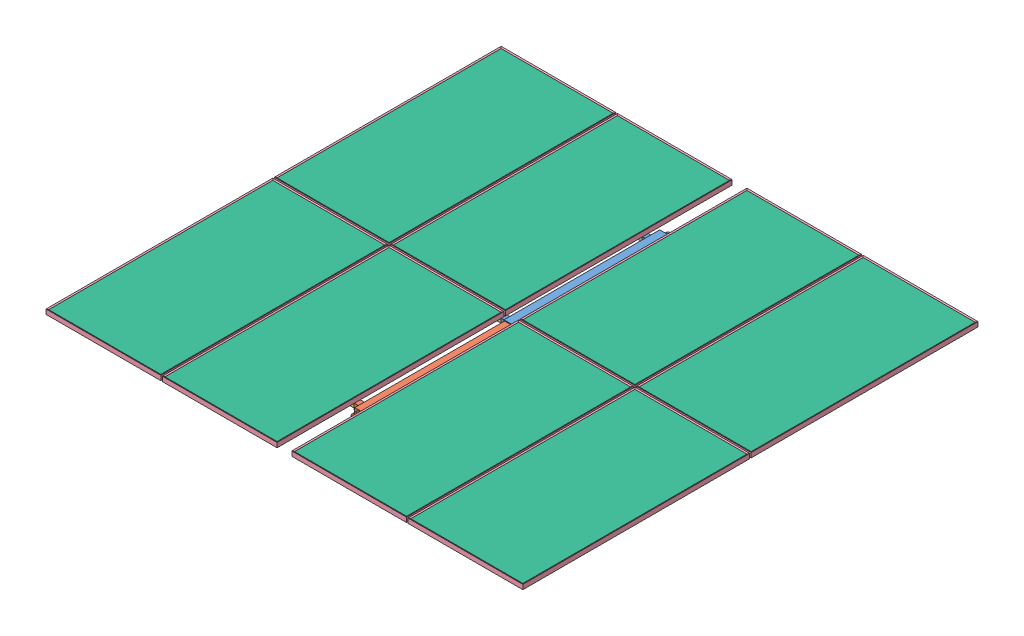
SolidWorks assembly SOLAR_ARRAY, configuration Default. Lengths in mm.
Overall size (4121.3 151.51 3933.6).
48 component instances, 7 part files, 65 mates.
Components (placement in the parent):
- SOLAR_FRAME_TELESCOPIC SLEEVE-1: SOLAR_FRAME_TELESCOPIC SLEEVE [Default] at (678.4072 800.4762 1616.3582) size (203.2 101.6 1384.3)
- SOLAR_FRAME_TELESCOPIC INSERT-1: SOLAR_FRAME_TELESCOPIC INSERT [Default] at (678.4072 800.4762 2911.7582) size (203.2 88.9 1612.9)
- SOLAR_FRAME_ARMBAR-1: SOLAR_FRAME_ARMBAR [Default] at (729.2072 800.4762 346.3582) x (0 0 1) z (-1 0 0) size (38.1 38.1 1828.8)
- SOLAR_FRAME_ARMBAR-2: SOLAR_FRAME_ARMBAR [Default] at (729.2072 800.4762 1565.5582) x (0 0 1) z (-1 0 0) size (38.1 38.1 1828.8)
- SOLAR_FRAME_ARMBAR-3: SOLAR_FRAME_ARMBAR [Default] at (729.2072 800.4762 2835.5582) x (0 0 -1) z (-1 0 0) size (38.1 38.1 1828.8)
- SOLAR_FRAME_ARMBAR-4: SOLAR_FRAME_ARMBAR [Default] at (627.6072 800.4762 346.3582) x (0 0 -1) z (1 0 0) size (38.1 38.1 1828.8)
- SOLAR_FRAME_ARMBAR-5: SOLAR_FRAME_ARMBAR [Default] at (627.6072 800.4762 1565.5582) x (0 0 -1) z (1 0 0) size (38.1 38.1 1828.8)
- SOLAR_FRAME_ARMBAR-6: SOLAR_FRAME_ARMBAR [Default] at (627.6072 800.4762 2835.5582) x (0 0 1) z (1 0 0) size (38.1 38.1 1828.8)
- SOLARPANEL-2: SOLARPANEL [Default] at (118.9072 880.5262 610.9582) size (992.9 40.66 1960.9)
  - SOLAR_PANEL_FRAM-1: SOLAR_PANEL_FRAM [Default] at origin size (992.9 40.66 1960.9)
  - SOLAR_PANEL_CELL-1: SOLAR_PANEL_CELL [Default] at (395 11.5 868.9962) x (0 0 -1) z (1 0 0) size (1956 21.55 988)
  - SOLAR_GLASS-1: SOLAR_GLASS [Default] at (0 11.8 0) x (0 0 1) z (-1 0 0) size (1956 3.2 988)
- SOLARPANEL-3: SOLARPANEL [Default] at (118.9072 880.5262 2583.6582) size (992.9 40.66 1960.9)
  - SOLAR_PANEL_FRAM-1: SOLAR_PANEL_FRAM [Default] at origin size (992.9 40.66 1960.9)
  - SOLAR_PANEL_CELL-1: SOLAR_PANEL_CELL [Default] at (395 11.5 868.9962) x (0 0 -1) z (1 0 0) size (1956 21.55 988)
  - SOLAR_GLASS-1: SOLAR_GLASS [Default] at (0 11.8 0) x (0 0 1) z (-1 0 0) size (1956 3.2 988)
- SOLARPANEL-4: SOLARPANEL [Default] at (1237.9072 880.5262 610.9582) size (992.9 40.66 1960.9)
  - SOLAR_PANEL_FRAM-1: SOLAR_PANEL_FRAM [Default] at origin size (992.9 40.66 1960.9)
  - SOLAR_PANEL_CELL-1: SOLAR_PANEL_CELL [Default] at (395 11.5 868.9962) x (0 0 -1) z (1 0 0) size (1956 21.55 988)
  - SOLAR_GLASS-1: SOLAR_GLASS [Default] at (0 11.8 0) x (0 0 1) z (-1 0 0) size (1956 3.2 988)
- SOLARPANEL-5: SOLARPANEL [Default] at (1237.9072 880.5262 2583.6582) size (992.9 40.66 1960.9)
  - SOLAR_PANEL_FRAM-1: SOLAR_PANEL_FRAM [Default] at origin size (992.9 40.66 1960.9)
  - SOLAR_PANEL_CELL-1: SOLAR_PANEL_CELL [Default] at (395 11.5 868.9962) x (0 0 -1) z (1 0 0) size (1956 21.55 988)
  - SOLAR_GLASS-1: SOLAR_GLASS [Default] at (0 11.8 0) x (0 0 1) z (-1 0 0) size (1956 3.2 988)
- SOLARPANEL-8: SOLARPANEL [Default] at (-885.7928 880.5262 610.9582) size (992.9 40.66 1960.9)
  - SOLAR_PANEL_FRAM-1: SOLAR_PANEL_FRAM [Default] at origin size (992.9 40.66 1960.9)
  - SOLAR_PANEL_CELL-1: SOLAR_PANEL_CELL [Default] at (395 11.5 868.9962) x (0 0 -1) z (1 0 0) size (1956 21.55 988)
  - SOLAR_GLASS-1: SOLAR_GLASS [Default] at (0 11.8 0) x (0 0 1) z (-1 0 0) size (1956 3.2 988)
- SOLARPANEL-9: SOLARPANEL [Default] at (-885.7928 880.5262 2583.6582) size (992.9 40.66 1960.9)
  - SOLAR_PANEL_FRAM-1: SOLAR_PANEL_FRAM [Default] at origin size (992.9 40.66 1960.9)
  - SOLAR_PANEL_CELL-1: SOLAR_PANEL_CELL [Default] at (395 11.5 868.9962) x (0 0 -1) z (1 0 0) size (1956 21.55 988)
  - SOLAR_GLASS-1: SOLAR_GLASS [Default] at (0 11.8 0) x (0 0 1) z (-1 0 0) size (1956 3.2 988)
- SOLARPANEL-10: SOLARPANEL [Default] at (2242.6072 880.5262 610.9582) size (992.9 40.66 1960.9)
  - SOLAR_PANEL_FRAM-1: SOLAR_PANEL_FRAM [Default] at origin size (992.9 40.66 1960.9)
  - SOLAR_PANEL_CELL-1: SOLAR_PANEL_CELL [Default] at (395 11.5 868.9962) x (0 0 -1) z (1 0 0) size (1956 21.55 988)
  - SOLAR_GLASS-1: SOLAR_GLASS [Default] at (0 11.8 0) x (0 0 1) z (-1 0 0) size (1956 3.2 988)
- SOLARPANEL-11: SOLARPANEL [Default] at (2242.6072 880.5262 2583.6582) size (992.9 40.66 1960.9)
  - SOLAR_PANEL_FRAM-1: SOLAR_PANEL_FRAM [Default] at origin size (992.9 40.66 1960.9)
  - SOLAR_PANEL_CELL-1: SOLAR_PANEL_CELL [Default] at (395 11.5 868.9962) x (0 0 -1) z (1 0 0) size (1956 21.55 988)
  - SOLAR_GLASS-1: SOLAR_GLASS [Default] at (0 11.8 0) x (0 0 1) z (-1 0 0) size (1956 3.2 988)
- Unistrut (1)-5: Unistrut (1) [Default] at (475.2072 840.0262 2949.8582) x (0 0 -1) z (1 0 0) size (2717.8 41 41)
- Unistrut (1)-6: Unistrut (1) [Default] at (-204.1928 840.0262 2949.8582) x (0 0 -1) z (1 0 0) size (2717.8 41 41)
- Unistrut (1)-7: Unistrut (1) [Default] at (-562.6928 840.0262 2949.8582) x (0 0 -1) z (1 0 0) size (2717.8 41 41)
- Unistrut (1)-8: Unistrut (1) [Default] at (-1056.4928 840.0262 2949.8582) x (0 0 -1) z (1 0 0) size (2717.8 41 41)
- Unistrut (1)-9: Unistrut (1) [Default] at (914.8072 840.0262 2949.8582) x (0 0 -1) z (1 0 0) size (2717.8 41 41)
- Unistrut (1)-10: Unistrut (1) [Default] at (1561.0072 840.0262 2949.8582) x (0 0 -1) z (1 0 0) size (2717.8 41 41)
- Unistrut (1)-11: Unistrut (1) [Default] at (1919.5072 840.0262 2949.8582) x (0 0 -1) z (1 0 0) size (2717.8 41 41)
- Unistrut (1)-12: Unistrut (1) [Default] at (2413.3072 840.0262 2949.8582) x (0 0 -1) z (1 0 0) size (2717.8 41 41)
Mates (geometry in assembly coordinates):
- Coincident1: coincident anti-aligned: plane of SOLAR_FRAME_TELESCOPIC SLEEVE-1 through (722.8572 844.9262 270.1582) normal (-1 0 0); plane of SOLAR_FRAME_TELESCOPIC INSERT-1 through (722.8572 844.9262 1336.9582) normal (1 0 0)
- Coincident2: coincident anti-aligned: plane of SOLAR_FRAME_TELESCOPIC SLEEVE-1 through (633.9572 844.9262 270.1582) normal (0 -1 0); plane of SOLAR_FRAME_TELESCOPIC INSERT-1 through (633.9572 844.9262 1336.9582) normal (0 1 0)
- Concentric1: concentric anti-aligned: circle of SOLAR_FRAME_TELESCOPIC INSERT-1; circle of SOLAR_FRAME_ARMBAR-3
- Coincident5: coincident anti-aligned: plane of SOLAR_FRAME_TELESCOPIC INSERT-1 through (780.0072 819.5262 2854.6082) normal (0 0 -1); plane of SOLAR_FRAME_ARMBAR-3 through (2558.0072 781.4262 2854.6082) normal (0 0 1)
- Coincident6: coincident anti-aligned: plane of SOLAR_FRAME_TELESCOPIC INSERT-1 through (780.0072 781.4262 2854.6082) normal (0 1 0); plane of SOLAR_FRAME_ARMBAR-3 through (2558.0072 781.4262 2854.6082) normal (0 -1 0)
- Coincident7: coincident anti-aligned: circle of SOLAR_FRAME_TELESCOPIC SLEEVE-1; circle of SOLAR_FRAME_ARMBAR-2
- Coincident8: coincident anti-aligned: plane of SOLAR_FRAME_TELESCOPIC SLEEVE-1 through (780.0072 781.4262 1584.6082) normal (0 1 0); plane of SOLAR_FRAME_ARMBAR-2 through (2558.0072 781.4262 1546.5082) normal (0 -1 0)
- Coincident9: coincident aligned: circle of SOLAR_FRAME_TELESCOPIC SLEEVE-1; circle of SOLAR_FRAME_ARMBAR-1
- Coincident10: coincident anti-aligned: plane of SOLAR_FRAME_TELESCOPIC SLEEVE-1 through (780.0072 781.4262 365.4082) normal (0 1 0); plane of SOLAR_FRAME_ARMBAR-1 through (2558.0072 781.4262 327.3082) normal (0 -1 0)
- Coincident13: coincident anti-aligned: circle of SOLAR_FRAME_TELESCOPIC SLEEVE-1; circle of SOLAR_FRAME_ARMBAR-4
- Coincident14: coincident anti-aligned: plane of SOLAR_FRAME_TELESCOPIC SLEEVE-1 through (576.8072 781.4262 327.3082) normal (0 1 0); plane of SOLAR_FRAME_ARMBAR-4 through (-1201.1928 781.4262 365.4082) normal (0 -1 0)
- Coincident16: coincident anti-aligned: circle of SOLAR_FRAME_TELESCOPIC SLEEVE-1; circle of SOLAR_FRAME_ARMBAR-5
- Coincident17: coincident anti-aligned: plane of SOLAR_FRAME_TELESCOPIC SLEEVE-1 through (576.8072 781.4262 1546.5082) normal (0 1 0); plane of SOLAR_FRAME_ARMBAR-5 through (-1201.1928 781.4262 1584.6082) normal (0 -1 0)
- Coincident18: coincident anti-aligned: circle of SOLAR_FRAME_TELESCOPIC INSERT-1; circle of SOLAR_FRAME_ARMBAR-6
- Coincident19: coincident anti-aligned: plane of SOLAR_FRAME_TELESCOPIC INSERT-1 through (576.8072 781.4262 2816.5082) normal (0 1 0); plane of SOLAR_FRAME_ARMBAR-6 through (-1201.1928 781.4262 2816.5082) normal (0 -1 0)
- Distance11: distance = 12.7 mm anti-aligned: plane of SOLARPANEL-2/SOLAR_PANEL_FRAM-1 through (615.1072 860.5262 1590.9582) normal (0 0 1); plane of SOLARPANEL-3/SOLAR_PANEL_FRAM-1 through (-377.2928 860.5262 1603.6582) normal (0 0 -1)
- Coincident39: coincident aligned: plane of SOLARPANEL-2/SOLAR_PANEL_FRAM-1 through (-377.0928 860.5262 1591.1582) normal (-1 0 0); plane of SOLARPANEL-3/SOLAR_PANEL_FRAM-1 through (-377.0928 860.5262 3563.8582) normal (-1 0 0)
- Coincident40: coincident aligned: plane of SOLARPANEL-2/SOLAR_PANEL_FRAM-1 through (-377.2928 860.5262 -334.0418) normal (0 -1 0); plane of SOLARPANEL-3/SOLAR_PANEL_FRAM-1 through (-377.2928 860.5262 1638.6582) normal (0 -1 0)
- Coincident41: coincident aligned: plane of SOLARPANEL-4/SOLAR_PANEL_FRAM-1 through (741.9072 860.5262 1591.1582) normal (-1 0 0); plane of SOLARPANEL-5/SOLAR_PANEL_FRAM-1 through (741.9072 860.5262 3563.8582) normal (-1 0 0)
- Distance8: distance = 12.7 mm anti-aligned: plane of SOLARPANEL-4/SOLAR_PANEL_FRAM-1 through (1734.1072 860.5262 1590.9582) normal (0 0 1); plane of SOLARPANEL-5/SOLAR_PANEL_FRAM-1 through (741.7072 860.5262 1603.6582) normal (0 0 -1)
- Coincident43: coincident aligned: plane of SOLARPANEL-4/SOLAR_PANEL_FRAM-1 through (741.7072 860.5262 -334.0418) normal (0 -1 0); plane of SOLARPANEL-5/SOLAR_PANEL_FRAM-1 through (741.7072 860.5262 1638.6582) normal (0 -1 0)
- Coincident47: coincident aligned: plane of SOLARPANEL-8/SOLAR_PANEL_FRAM-1 through (-1381.7928 860.5262 1591.1582) normal (-1 0 0); plane of SOLARPANEL-9/SOLAR_PANEL_FRAM-1 through (-1381.7928 860.5262 3563.8582) normal (-1 0 0)
- Distance7: distance = 12.7 mm anti-aligned: plane of SOLARPANEL-8/SOLAR_PANEL_FRAM-1 through (-389.5928 860.5262 1590.9582) normal (0 0 1); plane of SOLARPANEL-9/SOLAR_PANEL_FRAM-1 through (-1381.9928 860.5262 1603.6582) normal (0 0 -1)
- Coincident49: coincident aligned: plane of SOLARPANEL-8/SOLAR_PANEL_FRAM-1 through (-1381.9928 860.5262 -334.0418) normal (0 -1 0); plane of SOLARPANEL-9/SOLAR_PANEL_FRAM-1 through (-1381.9928 860.5262 1638.6582) normal (0 -1 0)
- Coincident50: coincident aligned: plane of SOLARPANEL-10/SOLAR_PANEL_FRAM-1 through (1746.6072 860.5262 1591.1582) normal (-1 0 0); plane of SOLARPANEL-11/SOLAR_PANEL_FRAM-1 through (1746.6072 860.5262 3563.8582) normal (-1 0 0)
- Distance9: distance = 12.7 mm anti-aligned: plane of SOLARPANEL-10/SOLAR_PANEL_FRAM-1 through (2738.8072 860.5262 1590.9582) normal (0 0 1); plane of SOLARPANEL-11/SOLAR_PANEL_FRAM-1 through (1746.4072 860.5262 1603.6582) normal (0 0 -1)
- Coincident52: coincident aligned: plane of SOLARPANEL-10/SOLAR_PANEL_FRAM-1 through (1746.4072 860.5262 -334.0418) normal (0 -1 0); plane of SOLARPANEL-11/SOLAR_PANEL_FRAM-1 through (1746.4072 860.5262 1638.6582) normal (0 -1 0)
- Distance12: distance = 12.7 mm anti-aligned: plane of SOLARPANEL-3/SOLAR_PANEL_FRAM-1 through (-377.0928 860.5262 3563.8582) normal (-1 0 0); plane of SOLARPANEL-9/SOLAR_PANEL_FRAM-1 through (-389.7928 860.5262 1603.4582) normal (1 0 0)
- Coincident54: coincident aligned: plane of SOLARPANEL-3/SOLAR_PANEL_FRAM-1 through (615.1072 860.5262 3563.6582) normal (0 0 1); plane of SOLARPANEL-9/SOLAR_PANEL_FRAM-1 through (-389.5928 860.5262 3563.6582) normal (0 0 1)
- Distance10: distance = 12.7 mm anti-aligned: plane of SOLARPANEL-5/SOLAR_PANEL_FRAM-1 through (1733.9072 860.5262 1603.4582) normal (1 0 0); plane of SOLARPANEL-11/SOLAR_PANEL_FRAM-1 through (1746.6072 860.5262 3563.8582) normal (-1 0 0)
- Coincident56: coincident aligned: plane of SOLARPANEL-5/SOLAR_PANEL_FRAM-1 through (1734.1072 860.5262 3563.6582) normal (0 0 1); plane of SOLARPANEL-11/SOLAR_PANEL_FRAM-1 through (2738.8072 860.5262 3563.6582) normal (0 0 1)
- Coincident57: coincident aligned: plane of SOLARPANEL-5/SOLAR_PANEL_FRAM-1 through (741.7072 860.5262 1638.6582) normal (0 -1 0); plane of SOLARPANEL-11/SOLAR_PANEL_FRAM-1 through (1746.4072 860.5262 1638.6582) normal (0 -1 0)
- Coincident58: coincident aligned: plane of SOLARPANEL-3/SOLAR_PANEL_FRAM-1 through (-377.2928 860.5262 1638.6582) normal (0 -1 0); plane of SOLARPANEL-9/SOLAR_PANEL_FRAM-1 through (-1381.9928 860.5262 1638.6582) normal (0 -1 0)
- Distance5: distance = 1358.9 mm: line of SOLARPANEL-2/SOLAR_PANEL_FRAM-1 through (614.9072 900.5262 1590.9582) axis (0 -1 0); plane of SOLAR_FRAME_TELESCOPIC SLEEVE-1 through (678.4072 800.4762 232.0582) normal (0 0 -1)
- Distance6: distance = 127 mm anti-aligned: plane of SOLARPANEL-2/SOLAR_PANEL_FRAM-1 through (614.9072 860.5262 -369.2418) normal (1 0 0); plane of SOLARPANEL-4/SOLAR_PANEL_FRAM-1 through (741.9072 860.5262 1591.1582) normal (-1 0 0)
- Parallel3: parallel anti-aligned: plane of SOLAR_FRAME_TELESCOPIC SLEEVE-1 through (627.6072 851.2762 270.1582) normal (-1 0 0); plane of SOLARPANEL-2/SOLAR_PANEL_FRAM-1 through (614.9072 860.5262 -369.2418) normal (1 0 0)
- Coincident64: coincident aligned: plane of SOLARPANEL-3/SOLAR_PANEL_FRAM-1 through (615.1072 860.5262 3563.6582) normal (0 0 1); plane of SOLARPANEL-5/SOLAR_PANEL_FRAM-1 through (1734.1072 860.5262 3563.6582) normal (0 0 1)
- Coincident65: coincident anti-aligned: plane of SOLAR_FRAME_ARMBAR-5 through (-1201.1928 819.5262 1584.6082) normal (0 1 0); plane of Unistrut (1)-5 through (494.7072 819.5262 232.0582) normal (0 -1 0)
- Parallel4: parallel anti-aligned: plane of SOLAR_FRAME_TELESCOPIC SLEEVE-1 through (627.6072 851.2762 270.1582) normal (-1 0 0); plane of Unistrut (1)-5 through (495.7072 820.5262 232.0582) normal (1 0 0)
- Coincident67: coincident aligned: plane of SOLAR_FRAME_TELESCOPIC SLEEVE-1 through (678.4072 800.4762 232.0582) normal (0 0 -1); plane of Unistrut (1)-5 through (455.7072 859.5262 232.0582) normal (0 0 -1)
- Distance13: distance = 152.4 mm: moEndPointRef_w of Unistrut (1)-5; plane of SOLAR_FRAME_TELESCOPIC SLEEVE-1 through (627.6072 851.2762 270.1582) normal (-1 0 0)
- Coincident69: coincident aligned: plane of Unistrut (1)-11 through (1900.0072 859.5262 232.0582) normal (0 0 -1); plane of Unistrut (1)-12 through (2393.8072 859.5262 232.0582) normal (0 0 -1)
- Coincident70: coincident aligned: plane of Unistrut (1)-10 through (1541.5072 859.5262 232.0582) normal (0 0 -1); plane of Unistrut (1)-11 through (1900.0072 859.5262 232.0582) normal (0 0 -1)
- Coincident71: coincident aligned: plane of Unistrut (1)-9 through (895.3072 859.5262 232.0582) normal (0 0 -1); plane of Unistrut (1)-10 through (1541.5072 859.5262 232.0582) normal (0 0 -1)
- Coincident72: coincident aligned: plane of SOLAR_FRAME_TELESCOPIC SLEEVE-1 through (678.4072 800.4762 232.0582) normal (0 0 -1); plane of Unistrut (1)-9 through (895.3072 859.5262 232.0582) normal (0 0 -1)
- Coincident73: coincident aligned: plane of Unistrut (1)-5 through (455.7072 859.5262 232.0582) normal (0 0 -1); plane of Unistrut (1)-6 through (-223.6928 859.5262 232.0582) normal (0 0 -1)
- Coincident74: coincident aligned: plane of Unistrut (1)-6 through (-223.6928 859.5262 232.0582) normal (0 0 -1); plane of Unistrut (1)-7 through (-481.891 859.5262 232.0582) normal (0 0 -1)
- Coincident75: coincident: plane of Unistrut (1)-7 through (-582.1928 859.5262 232.0582) normal (0 0 -1); plane of Unistrut (1)-8 through (-1076.0412 859.5262 232.0582) normal (0 0 -1)
- Coincident76: coincident aligned: plane of Unistrut (1)-5 through (494.7072 819.5262 232.0582) normal (0 -1 0); plane of Unistrut (1)-6 through (-184.6928 819.5262 232.0582) normal (0 -1 0)
- Coincident77: coincident aligned: plane of Unistrut (1)-6 through (-184.6928 819.5262 232.0582) normal (0 -1 0); plane of Unistrut (1)-7 through (-442.891 819.5262 232.0582) normal (0 -1 0)
- Coincident78: coincident: plane of Unistrut (1)-7 through (-543.1928 819.5262 232.0582) normal (0 -1 0); plane of Unistrut (1)-8 through (-1037.0412 819.5262 232.0582) normal (0 -1 0)
- Coincident79: coincident anti-aligned: plane of SOLAR_FRAME_ARMBAR-2 through (2558.0072 819.5262 1546.5082) normal (0 1 0); plane of Unistrut (1)-9 through (934.3072 819.5262 232.0582) normal (0 -1 0)
- Coincident80: coincident aligned: plane of Unistrut (1)-9 through (934.3072 819.5262 232.0582) normal (0 -1 0); plane of Unistrut (1)-10 through (1580.5072 819.5262 232.0582) normal (0 -1 0)
- Coincident81: coincident aligned: plane of Unistrut (1)-10 through (1580.5072 819.5262 232.0582) normal (0 -1 0); plane of Unistrut (1)-11 through (1939.0072 819.5262 232.0582) normal (0 -1 0)
- Coincident82: coincident aligned: plane of Unistrut (1)-11 through (1939.0072 819.5262 232.0582) normal (0 -1 0); plane of Unistrut (1)-12 through (2432.8072 819.5262 232.0582) normal (0 -1 0)
- Coincident83: coincident anti-aligned: plane of SOLARPANEL-4/SOLAR_PANEL_FRAM-1 through (741.7072 860.5262 -334.0418) normal (0 -1 0); plane of Unistrut (1)-9 through (902.8072 860.5262 232.0582) normal (0 1 0)
- Coincident84: coincident anti-aligned: plane of SOLARPANEL-2/SOLAR_PANEL_FRAM-1 through (-377.2928 860.5262 -334.0418) normal (0 -1 0); plane of Unistrut (1)-5 through (494.7072 860.5262 232.0582) normal (0 1 0)
- Distance14: distance = 12.7 mm anti-aligned: plane of SOLARPANEL-2/SOLAR_PANEL_FRAM-1 through (614.9072 860.5262 -369.2418) normal (1 0 0); plane of SOLAR_FRAME_TELESCOPIC SLEEVE-1 through (627.6072 851.2762 270.1582) normal (-1 0 0)
- Distance15: distance = 304.8 mm aligned: plane of SOLARPANEL-10/SOLAR_PANEL_FRAM-1 through (2738.6072 860.5262 -369.2418) normal (1 0 0); plane of Unistrut (1)-12 through (2433.8072 820.5262 232.0582) normal (1 0 0)
- Distance16: distance = 152.4 mm aligned: plane of SOLARPANEL-10/SOLAR_PANEL_FRAM-1 through (1746.6072 860.5262 1591.1582) normal (-1 0 0); plane of Unistrut (1)-11 through (1899.0072 820.5262 232.0582) normal (-1 0 0)
- Distance17: distance = 152.4 mm aligned: plane of SOLARPANEL-4/SOLAR_PANEL_FRAM-1 through (1733.9072 860.5262 -369.2418) normal (1 0 0); plane of Unistrut (1)-10 through (1581.5072 820.5262 232.0582) normal (1 0 0)
- Distance18: distance = 152.4 mm aligned: plane of SOLARPANEL-4/SOLAR_PANEL_FRAM-1 through (741.9072 860.5262 1591.1582) normal (-1 0 0); plane of Unistrut (1)-9 through (894.3072 820.5262 232.0582) normal (-1 0 0)
- Distance20: distance = 152.4 mm aligned: plane of SOLARPANEL-2/SOLAR_PANEL_FRAM-1 through (-377.0928 860.5262 1591.1582) normal (-1 0 0); plane of Unistrut (1)-6 through (-224.6928 820.5262 232.0582) normal (-1 0 0)
- Distance21: distance = 152.4 mm aligned: plane of SOLARPANEL-8/SOLAR_PANEL_FRAM-1 through (-389.7928 860.5262 -369.2418) normal (1 0 0); plane of Unistrut (1)-7 through (-542.1928 820.5262 232.0582) normal (1 0 0)
- Distance22: distance = 304.8 mm aligned: plane of SOLARPANEL-8/SOLAR_PANEL_FRAM-1 through (-1381.7928 860.5262 1591.1582) normal (-1 0 0); plane of Unistrut (1)-8 through (-1076.9928 820.5262 232.0582) normal (-1 0 0)
